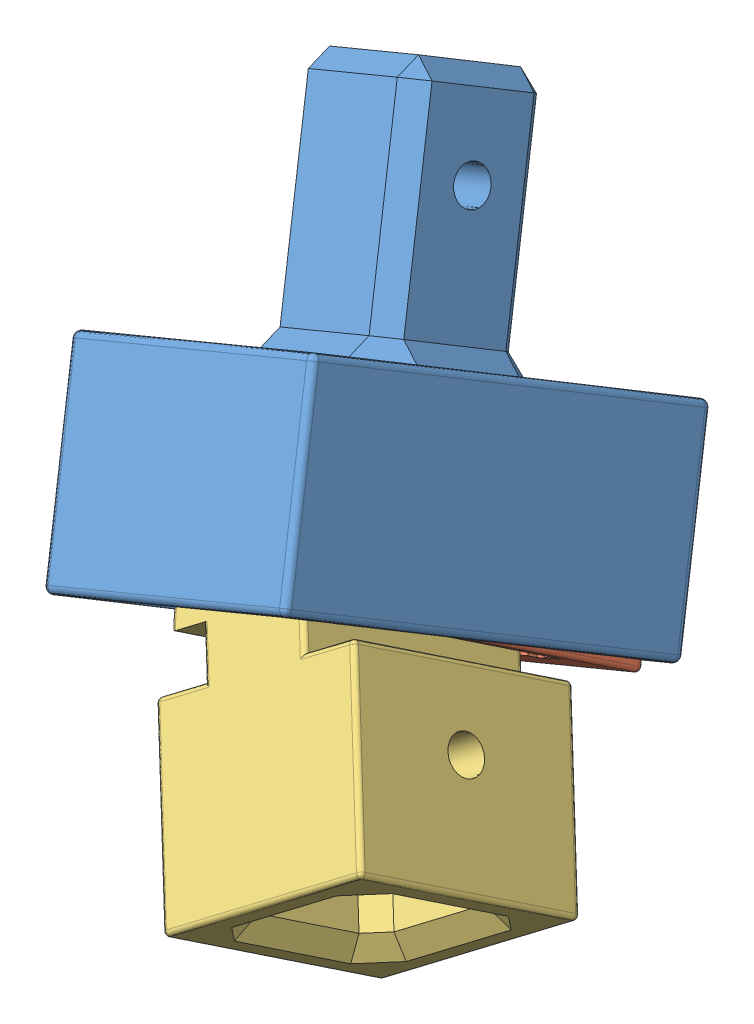
SolidWorks assembly 01_01_01_ML, configuration Default. Lengths in mm.
3 component instances, 3 part files, 8 mates.
Components (placement in the parent):
- 01_01_01_01_ML-2: 01_01_01_01_ML [Default] at (25.4696 -21.8257 0.178) x (0.186911 -0.450738 -0.872869) z (0.923728 0.383049 0) size (54.63 59.06 38.1)
- 01_01_01_02_ML-2: 01_01_01_02_ML [Default] at (25.4696 -21.8257 0.178) x (-0.923728 -0.383049 0) z (0.205768 -0.496213 -0.843465) size (35.56 24.14 48.26)
- 01_01_01_03_ML-1: 01_01_01_03_ML [Default] at (25.4696 -21.8257 0.178) x (0.803816 0.577303 -0.143533) z (-0.205768 0.496213 0.843465) size (30.35 44.2 33.02)
Mates (geometry in assembly coordinates):
- Concentric1: concentric aligned: circle of InnerHinge-1; circle of 01_01_01_07_ML-1
- Width1: width: plane of InnerHinge-1 through (25.9657 6.8566 -16.3359) normal (0 0.175409 0.984496); plane of InnerHinge-1 through (25.9657 12.2031 13.6715) normal (0 -0.175409 -0.984496); plane of 01_01_01_03_ML-1 through (28.5924 -29.3565 -12.6228) normal (0.205768 -0.496213 -0.843465); plane of 01_01_01_03_ML-1 through (22.3468 -14.2949 12.9789) normal (-0.205768 0.496213 0.843465)
- Concentric2: concentric anti-aligned: circle of AnkleJointOuterHinge-1; circle of InnerHinge-1
- Width2: width: plane of AnkleJointOuterHinge-1 through (9.4557 9.5299 -1.3322) normal (1 0 0); plane of InnerHinge-1 through (42.4757 9.5299 -1.3322) normal (-1 0 0); plane of AnkleJointOuterHinge-1 through (9.4557 19.1684 -4.017) normal (-1 0 0); plane of InnerHinge-1 through (42.4757 19.1684 -4.017) normal (1 0 0)
- Concentric3: concentric anti-aligned: circle of 01_01_01_07_ML-1; circle of InnerHinge-2
- Width3: width: plane of 01_01_01_02_ML-2 through (22.0724 -13.6332 14.1036) normal (0.205768 -0.496213 -0.843465); plane of 01_01_01_02_ML-2 through (28.8668 -30.0182 -13.7476) normal (-0.205768 0.496213 0.843465); plane of 01_01_01_03_ML-1 through (22.0724 -13.6332 14.1036) normal (-0.205768 0.496213 0.843465); plane of 01_01_01_03_ML-1 through (28.8668 -30.0182 -13.7476) normal (0.205768 -0.496213 -0.843465)
- Concentric4: concentric anti-aligned: circle of AnkleJointOuterHinge-2; circle of InnerHinge-2
- Width4: width: plane of 01_01_01_01_ML-2 through (41.8935 -15.0151 0.178) normal (-0.923728 -0.383049 0); plane of 01_01_01_01_ML-2 through (9.0457 -28.6363 0.178) normal (0.923728 0.383049 0); plane of 01_01_01_02_ML-2 through (38.9194 -7.843 -6.1326) normal (0.923728 0.383049 0); plane of 01_01_01_02_ML-2 through (6.0716 -21.4642 -6.1326) normal (-0.923728 -0.383049 0)
